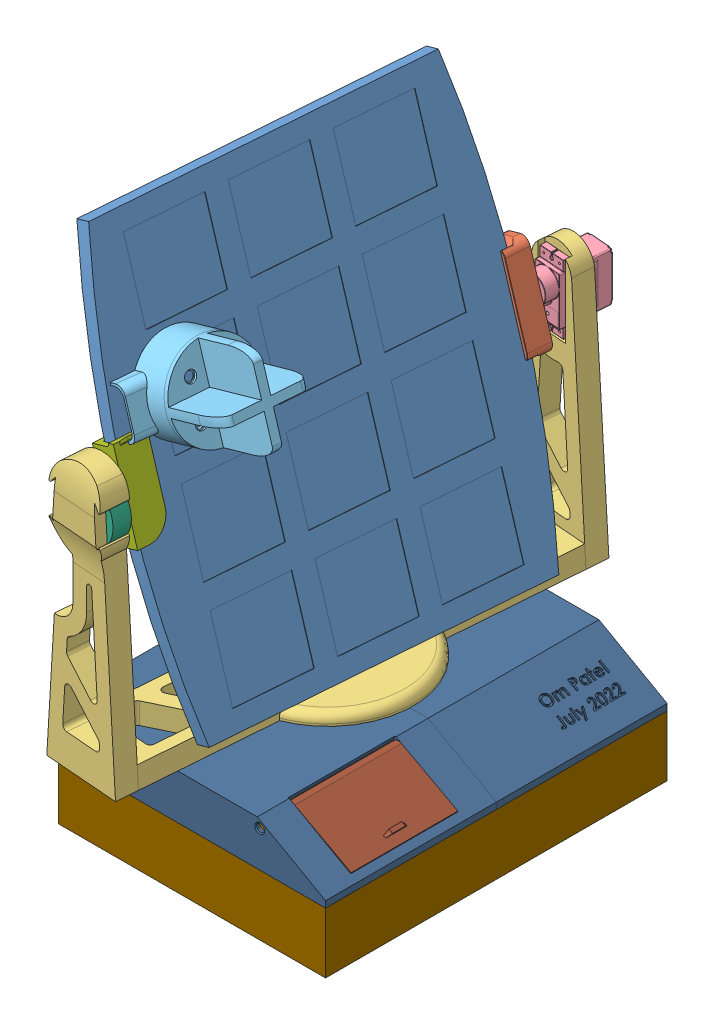
SolidWorks assembly Assem1, configuration Default. Lengths in mm.
Overall size (137.17 250.74 232.94).
11 component instances, 11 part files, 27 mates.
Components (placement in the parent):
- solar panel-1: solar panel [Default] at (14.9115 150.7231 5.8386) x (0.077892 0 -0.996962) z (-0.321387 0.946615 -0.02511) size (171.45 26.35 190.5)
- stand1-1: stand1 [Default] at (1.2858 171.1581 4.7741) x (0.077892 0 -0.996962) z (-0.943739 -0.322366 -0.073734) size (102.52 60 18.02)
- frame-1: frame [Default] at (1.5039 165.3 -0.7419) x (0.077892 0 -0.996962) z (0.996962 0 0.077892) size (218.74 127.71 80)
- Tower-Pro-MG90S-1: Tower-Pro-MG90S [Valor predeterminado] at (20.2146 144.0402 -117.9406) x (0 1 0) z (0.996962 0 0.077892) size (32.1 32.51 12.5)
- sensor-1: sensor [Default] at (17.557 183.1108 60.9371) x (-0.321387 0.946615 -0.02511) z (0.077892 0 -0.996962) size (40.15 47.06 47.57)
- bearing-1: bearing [Default] at (2.7746 149.2402 105.2792) x (0.077892 0 -0.996962) z (0.80059 -0.595939 0.06255) size (8 28 28)
- stand2-1: stand2 [Default] at (5.2379 149.6996 91.0691) x (0.077892 0 -0.996962) z (-0.943739 -0.322366 -0.073734) size (37.67 38.5 11.85)
- servo-2: servo [Default] at origin size (55.5 44 20)
- box-1: box [Default] at (-0.075 -3.5 0) x (0 0 1) z (-1 0 0) size (160 28.85 125)
- topcover-1: topcover [Default] at (27.425 16.5 0) x (0 0 -1) z (1 0 0) size (182.88 23 125)
- door-1: door [Default] at (72.7554 29.1952 40) x (0 0 -1) z (0.880877 -0.473346 0) size (50 8 33)
Mates (geometry in assembly coordinates):
- Coincident1: coincident anti-aligned: plane of solar panel-1 through (-21.871 148.676 399.457) normal (-0.943739 -0.322366 -0.073734); plane of stand1-1 through (1.2858 171.1581 4.7741) normal (0.943739 0.322366 0.073734)
- Width1: width anti-aligned: plane of stand1-1 through (4.9591 156.3142 -4.4679) normal (0.077892 0 -0.996962); plane of stand1-1 through (3.4792 156.3142 14.4744) normal (-0.077892 0 0.996962); plane of solar panel-1 through (-5.1256 186.1326 -5.7573) normal (-0.077892 0 0.996962); plane of solar panel-1 through (-6.6834 186.1326 14.1819) normal (0.077892 0 -0.996962)
- Coincident2: coincident anti-aligned: plane of solar panel-1 through (-16.6627 150.5116 53.5241) normal (-0.321387 0.946615 -0.02511); plane of stand1-1 through (3.4792 156.3142 14.4744) normal (0.321387 -0.946615 0.02511)
- Distance1: distance = 31.3 mm aligned: plane of Tower-Pro-MG90S-1 through (14.0724 132.6402 -118.922) normal (0.077892 0 -0.996962); plane of stand1-1 through (8.5311 171.1581 -87.9595) normal (0.077892 0 -0.996962)
- Concentric1: concentric aligned: cylinder of stand1-1 through (17.5819 149.2402 -84.2433) axis (0.077892 0 -0.996962) radius 3.75; cylinder of Tower-Pro-MG90S-1 through (17.9713 149.2402 -89.2281) axis (0.077892 0 -0.996962) radius 6.2
- Coincident3: coincident anti-aligned: plane of frame-1 through (9.3321 165.3 -100.9366) normal (-0.077892 0 0.996962); plane of Tower-Pro-MG90S-1 through (18.8282 144.0402 -100.1947) normal (0.077892 0 -0.996962)
- Width5: width anti-aligned: plane of frame-1 through (8.9323 132.5402 107.6671) normal (0 1 0); plane of Tower-Pro-MG90S-1 through (8.9323 155.5402 107.6671) normal (0 -1 0); plane of frame-1 through (12.2575 132.6402 -95.6928) normal (0 -1 0); plane of Tower-Pro-MG90S-1 through (12.2575 155.4402 -95.6928) normal (0 1 0)
- Coincident6: coincident anti-aligned: plane of solar panel-1 through (-15.8782 150.7231 399.9252) normal (0.943739 0.322366 0.073734); plane of sensor-1 through (1.5135 177.6306 59.6836) normal (-0.943739 -0.322366 -0.073734)
- Concentric2: concentric anti-aligned: cylinder of frame-1 through (2.7746 149.2402 105.2792) axis (0.077892 0 -0.996962) radius 14.025; cylinder of bearing-1 through (3.3977 149.2402 97.3035) axis (-0.077892 0 0.996962) radius 14
- Coincident8: coincident anti-aligned: plane of frame-1 through (2.7746 149.2402 105.2792) normal (0.077892 0 -0.996962); plane of bearing-1 through (2.7746 149.2402 105.2792) normal (-0.077892 0 0.996962)
- Concentric5: concentric anti-aligned: cylinder of bearing-1 through (3.3977 149.2402 97.3035) axis (-0.077892 0 0.996962) radius 6; cylinder of stand2-1 through (2.9057 149.2402 103.6005) axis (0.077892 0 -0.996962) radius 5.925
- Parallel7: parallel aligned: plane of solar panel-1 through (-21.871 148.676 399.457) normal (-0.943739 -0.322366 -0.073734); plane of stand2-1 through (5.3835 130.2772 93.7636) normal (-0.943739 -0.322366 -0.073734)
- Tangent2: tangent anti-aligned: cylinder of solar panel-1 through (39.7086 148.676 -388.7161) axis (0.943739 0.322366 0.073734) radius 481.0125; plane of stand2-1 through (14.2507 133.2349 91.7733) normal (0.077892 0 -0.996962)
- Parallel9: parallel anti-aligned: plane of solar panel-1; plane of frame-1 through (-97.5 -114.3 19.05) normal (0 1 0)
- Coincident21: coincident anti-aligned: plane of sensor-1 through (-0.8141 199.407 87.0856) normal (-0.077892 0 0.996962); plane of stand2-1 through (-0.0821 147.7892 87.1428) normal (0.077892 0 -0.996962)
- Width7: width aligned: plane of sensor-1 through (2.2992 167.2178 95.1514) normal (0.321387 -0.946615 0.02511); plane of stand2-1 through (9.2981 170.2598 80.4265) normal (-0.321387 0.946615 -0.02511); plane of sensor-1 through (3.8497 168.8399 93.6438) normal (0.321387 -0.946615 0.02511); plane of stand2-1 through (-5.9308 164.213 90.1965) normal (-0.321387 0.946615 -0.02511)
- Width8: width anti-aligned: plane of Tower-Pro-MG90S-1 through (24.6199 132.6402 -94.7269) normal (0.996962 0 0.077892); plane of frame-1 through (12.2575 132.6402 -95.6928) normal (-0.996962 0 -0.077892); plane of Tower-Pro-MG90S-1 through (8.9323 155.5402 107.6671) normal (-0.996962 0 -0.077892); plane of frame-1 through (-3.6793 155.5402 106.6817) normal (0.996962 0 0.077892)
- Concentric7: concentric anti-aligned: cone of frame-1 through (11 44 0) axis (0 -1 0); cylinder of servo-2 through (11 42 0) axis (0 1 0) radius 6.5
- Coincident23: coincident anti-aligned: plane of frame-1 through (19.5107 44 0.6649) normal (0 -1 0); plane of servo-2 through (11 44 0) normal (0 1 0)
- Coincident24: coincident anti-aligned: plane of servo-2 through (20.5 36 10) normal (1 0 0); plane of box-1 through (20.5 19 -10.075) normal (-1 0 0)
- Width9: width anti-aligned: plane of box-1 through (-20.65 19 -10.075) normal (0 0 1); plane of box-1 through (-20.65 19 10.075) normal (0 0 -1); plane of servo-2 through (-20.5 36 -10) normal (0 0 -1); plane of servo-2 through (-20.5 36 10) normal (0 0 1)
- Width10: width anti-aligned: plane of topcover-1 through (89.925 39.5 80) normal (1 0 0); plane of box-1 through (-35.075 39.5 80) normal (-1 0 0); plane of topcover-1 through (-35.075 -9.85 -80) normal (-1 0 0); plane of box-1 through (89.925 -9.85 -80) normal (1 0 0)
- Width11: width anti-aligned: plane of topcover-1 through (-35.075 39.5 -80) normal (0 0 -1); plane of box-1 through (-35.075 39.5 80) normal (0 0 1); plane of topcover-1 through (89.925 -9.85 80) normal (0 0 1); plane of box-1 through (89.925 -9.85 -80) normal (0 0 -1)
- Coincident25: coincident anti-aligned: plane of box-1 through (-0.075 16.5 0) normal (0 1 0); plane of topcover-1 through (27.425 16.5 0) normal (0 -1 0)
- Coincident29: coincident: line of topcover-1; line of door-1 through (86.9153 23.8567 15) axis (-0.880877 0.473346 0)
- Concentric9: concentric aligned: cylinder of topcover-1 through (59.0689 35.4145 -44) axis (0 0 1) radius 1.8; cylinder of door-1 through (59.0689 35.4145 6.5147) axis (0 0 1) radius 3
- Coincident30: coincident anti-aligned: plane of servo-2 through (0 0 0) normal (0 -1 0); plane of box-1 through (-0.075 0 0) normal (0 1 0)
